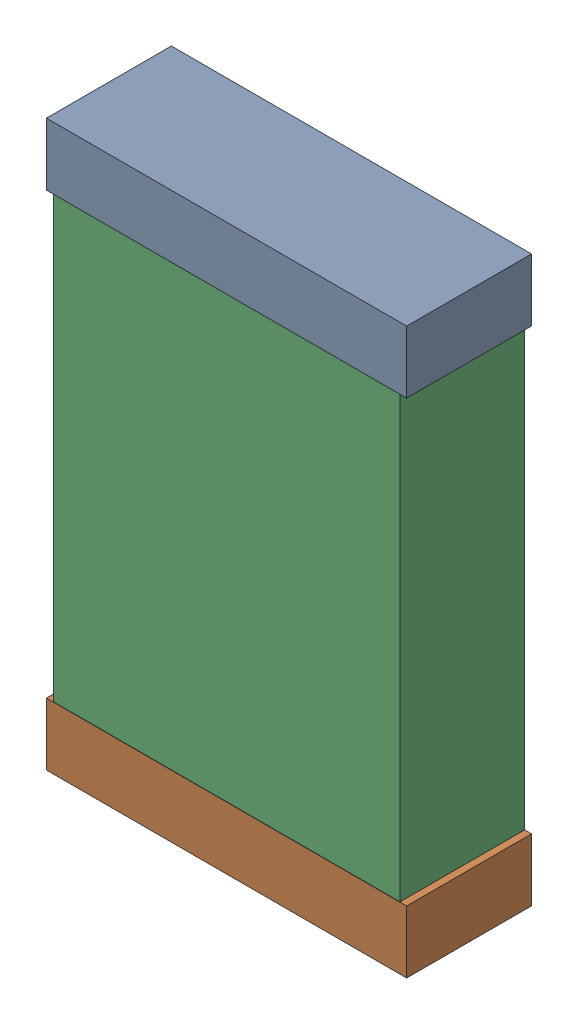
SolidWorks assembly C52, configuration Default. Lengths in mm.
Overall size (1.3 2.04 0.45).
6 component instances, 2 part files, 0 mates.
Components (placement in the parent):
- 740902240-1: 740902240 [Default] at (69.5952 17.9666 0) size (1.3 0.23 0.45)
  - Extruded_35-1: Extruded_35 [Default] at origin size (1.3 0.23 0.45)
- 740902240-2: 740902240 [Default] at (69.5952 16.1541 0) size (1.3 0.23 0.45)
  - Extruded_35-1: Extruded_35 [Default] at origin size (1.3 0.23 0.45)
- 740904480-1: 740904480 [Default] at (69.5952 17.0666 0) size (1.25 2 0.45)
  - Extruded_34-1: Extruded_34 [Default] at origin size (1.25 2 0.45)
